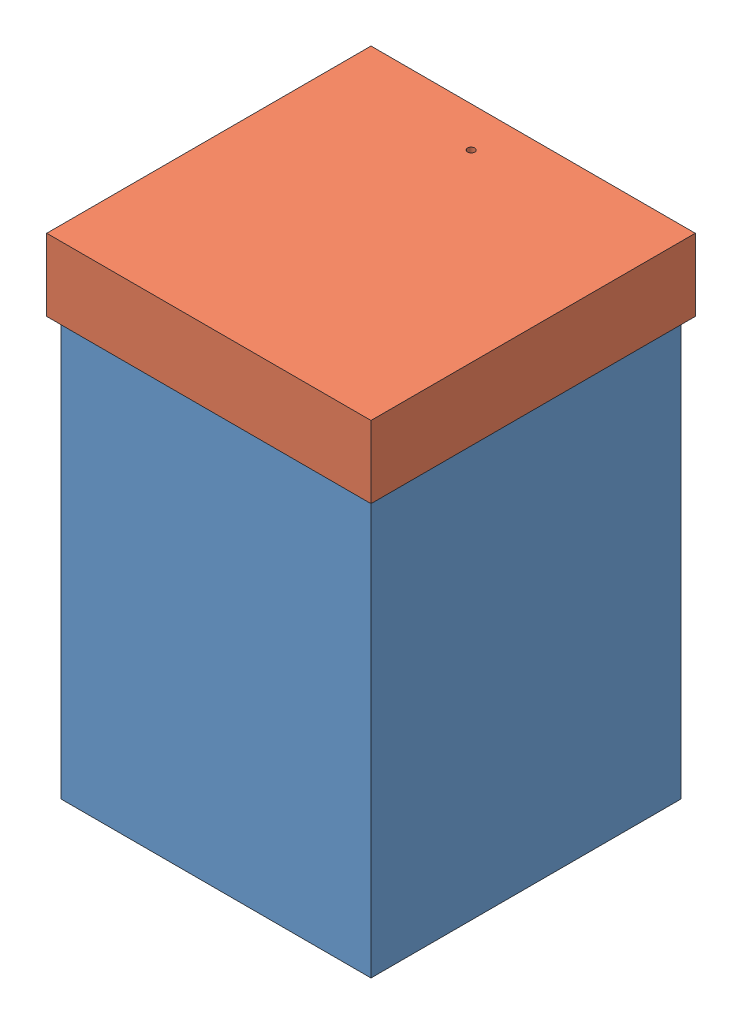
SolidWorks assembly payload_box, configuration Default. Lengths in mm.
Overall size (450 680 450).
2 component instances, 2 part files, 4 mates.
Components (placement in the parent):
- payload_bottom-1: payload_bottom [Default] at (208.3996 -10.2966 514.0506) size (430 630 430)
- Part1^payload_box-1: Part1^payload_box [Default] at (208.3996 619.7034 514.0506) x (1 0 0) z (0 1 0) size (450 450 100) (virtual)
Mates (geometry in assembly coordinates):
- InPlace1: in place: plane of payload_bottom-1 through (208.3996 619.7034 514.0506) normal (0 1 0); plane of ? through (0 619.7034 0) normal (0 1 0); moOrthogonalPlaneRef_w of payload_bottom-1 through (208.3996 619.7034 514.0506) normal (0 1 0); plane of ? through (0 619.7034 0) normal (0 0 -1); plane of payload_bottom-1 through (208.3996 619.7034 514.0506) normal (0 1 0); line of ? through (-55 0 619.7034) axis (0 1 0); plane of payload_bottom-1 through (208.3996 619.7034 514.0506) normal (0 1 0); unknown of Part1^payload_box-1
- Coincident1: coincident aligned: plane of payload_bottom-1; plane of Part1^payload_box-1
- Coincident2: coincident aligned: moOrthogonalPlaneRef_w of payload_bottom-1 through (208.3996 619.7034 514.0506) normal (0 0 -1); plane of Part1^payload_box-1 through (208.3996 619.7034 514.0506) normal (0 0 -1)
- Coincident3: coincident anti-aligned: moOrthogonalPlaneRef_w of payload_bottom-1 through (208.3996 619.7034 514.0506) normal (-1 0 0); plane of Part1^payload_box-1
